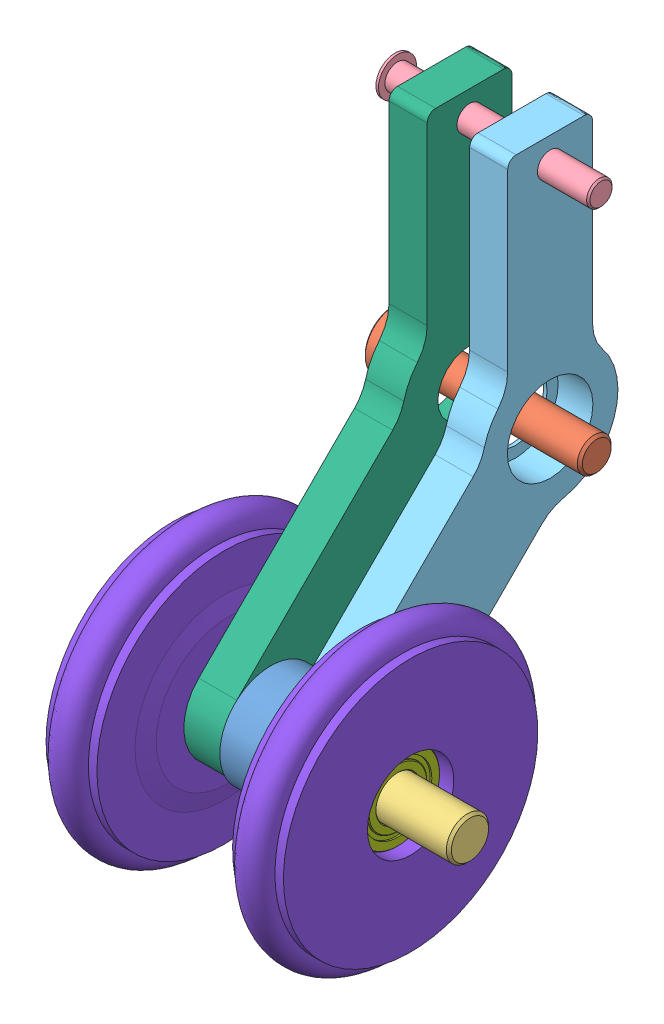
SolidWorks assembly 防震承重轮总成-右, configuration 默认. Lengths in mm.
Overall size (38 75.35 53.59).
10 component instances, 8 part files, 18 mates.
Components (placement in the parent):
- 摇臂间隔圈-1: 摇臂间隔圈 [默认] at (-55.6909 -27.5217 46.528) x (1 0 0) z (0 -0.74001 0.672596) size (5 12 12)
- M4X20mm内六角螺钉-1: M4X20mm内六角螺钉 [默认] at (-60.6909 -4.3053 23.0759) x (0 0.672462 -0.740132) z (0 0.740132 0.672462) size (7 24 7)
- M5X34mm内六角螺钉-1: M5X34mm内六角螺钉 [默认] at (-66.1909 -27.5217 46.528) x (0 0.979357 0.202139) z (0 -0.202139 0.979357) size (8 38 8)
- M3X40圆头螺钉-1: M3X40圆头螺钉 [默认] at (-64.1909 22.6947 23.0759) x (-1 0 0) z (0 0.426607 -0.904437) size (25.38 4.5 4.5)
- 减震轮摇臂-右-1: 减震轮摇臂-右 [默认] at (-48.4409 -4.3053 23.0759) size (4.5 58.97 37.21)
- 减震轮摇臂-左-1: 减震轮摇臂-左 [默认] at (-57.9409 -4.3053 23.0759) size (4.5 58.97 37.21)
- 5X10X4轴承-1: 5X10X4轴承 [默认] at (-44.6909 -27.5217 46.528) size (4 10 10)
- 5X10X4轴承-2: 5X10X4轴承 [默认] at (-65.6909 -27.5217 46.528) size (4 10 10)
- 防震承重轮-左右通用-1: 防震承重轮-左右通用 [默认] at (-39.1909 -27.5217 46.528) x (-1 0 0) z (0 -0.924225 -0.381849) size (6.5 33.9 33.9)
- 防震承重轮-左右通用-2: 防震承重轮-左右通用 [默认] at (-67.1909 -27.5217 46.528) size (6.5 33.9 33.9)
Mates (geometry in assembly coordinates):
- 同心12: concentric anti-aligned: circle of 摇臂间隔圈-1; cylinder of M5X34mm内六角螺钉-1 through (-32.1909 -27.5217 46.528) axis (-1 0 0) radius 2.5
- 同心22: concentric anti-aligned: cylinder of M5X34mm内六角螺钉-1 through (-32.1909 -27.5217 46.528) axis (-1 0 0) radius 2.5; cylinder of 减震轮摇臂-右-1 through (-50.6909 -27.5217 46.528) axis (1 0 0) radius 2.7
- 同心23: concentric anti-aligned: cylinder of M5X34mm内六角螺钉-1 through (-32.1909 -27.5217 46.528) axis (-1 0 0) radius 2.5; cylinder of 减震轮摇臂-左-1 through (-60.1909 -27.5217 46.528) axis (1 0 0) radius 2.7
- 重合4: coincident anti-aligned: plane of 摇臂间隔圈-1 through (-50.6909 -27.5217 46.528) normal (1 0 0); plane of 减震轮摇臂-右-1 through (-50.6909 -27.2789 46.2852) normal (-1 0 0)
- 重合5: coincident anti-aligned: plane of 摇臂间隔圈-1 through (-55.6909 -27.5217 46.528) normal (-1 0 0); plane of 减震轮摇臂-左-1 through (-55.6909 -27.2789 46.2852) normal (1 0 0)
- 同心25: concentric anti-aligned: cylinder of M3X40圆头螺钉-1 through (-40.1909 22.6947 23.0759) axis (-1 0 0) radius 1.5; cylinder of 减震轮摇臂-左-1 through (-61.6909 22.6947 23.0759) axis (1 0 0) radius 1.25
- 同心26: concentric aligned: cylinder of M5X34mm内六角螺钉-1 through (-32.1909 -27.5217 46.528) axis (-1 0 0) radius 2.5; cylinder of 5X10X4轴承-2 through (-61.6909 -27.5217 46.528) axis (-1 0 0) radius 2.5
- 同心27: concentric aligned: cylinder of M5X34mm内六角螺钉-1 through (-32.1909 -27.5217 46.528) axis (-1 0 0) radius 2.5; cylinder of 5X10X4轴承-1 through (-40.6909 -27.5217 46.528) axis (-1 0 0) radius 2.5
- 同心29: concentric anti-aligned: cylinder of 5X10X4轴承-1 through (-40.6909 -27.5217 46.528) axis (-1 0 0) radius 5; cylinder of 防震承重轮-左右通用-1 through (-39.1909 -27.5217 46.528) axis (1 0 0) radius 5.1
- 重合6: coincident anti-aligned: plane of 5X10X4轴承-1 through (-44.6909 -27.5217 46.528) normal (-1 0 0); plane of 防震承重轮-左右通用-1 through (-44.6909 -25.5743 41.8144) normal (1 0 0)
- 距离1: distance = 0.5 mm anti-aligned: plane of 减震轮摇臂-右-1 through (-46.1909 -27.2789 46.2852) normal (1 0 0); plane of 防震承重轮-左右通用-1 through (-45.6909 -24.276 38.6721) normal (-1 0 0)
- 同心30: concentric aligned: cylinder of 5X10X4轴承-2 through (-61.6909 -27.5217 46.528) axis (-1 0 0) radius 5; cylinder of 防震承重轮-左右通用-2 through (-67.1909 -27.5217 46.528) axis (-1 0 0) radius 5.1
- 重合8: coincident anti-aligned: plane of 5X10X4轴承-2 through (-61.6909 -27.5217 46.528) normal (1 0 0); plane of 防震承重轮-左右通用-2 through (-61.6909 -22.4217 46.528) normal (-1 0 0)
- 距离3: distance = 0.5 mm anti-aligned: plane of 防震承重轮-左右通用-2 through (-60.6909 -19.0217 46.528) normal (1 0 0); plane of 减震轮摇臂-左-1 through (-60.1909 -27.2789 46.2852) normal (-1 0 0)
- 距离4: distance = 0.5 mm anti-aligned: plane of 5X10X4轴承-2 through (-65.6909 -27.5217 46.528) normal (-1 0 0); plane of M5X34mm内六角螺钉-1 through (-66.1909 -27.5217 46.528) normal (1 0 0)
- 同心31: concentric aligned: cylinder of M4X20mm内六角螺钉-1 through (-40.6909 -4.3053 23.0759) axis (-1 0 0) radius 2; cylinder of 减震轮摇臂-左-1 through (-56.0909 -4.3053 23.0759) axis (-1 0 0) radius 5.05
- 距离5: distance = 0.5 mm anti-aligned: plane of 减震轮摇臂-左-1 through (-60.1909 -27.2789 46.2852) normal (-1 0 0); plane of M4X20mm内六角螺钉-1 through (-60.6909 -4.3053 23.0759) normal (1 0 0)
- 距离6: distance = 6 mm aligned: plane of 减震轮摇臂-右-1 through (-46.1909 -27.2789 46.2852) normal (1 0 0); plane of M3X40圆头螺钉-1 through (-40.1909 22.6947 23.0759) normal (1 0 0)
